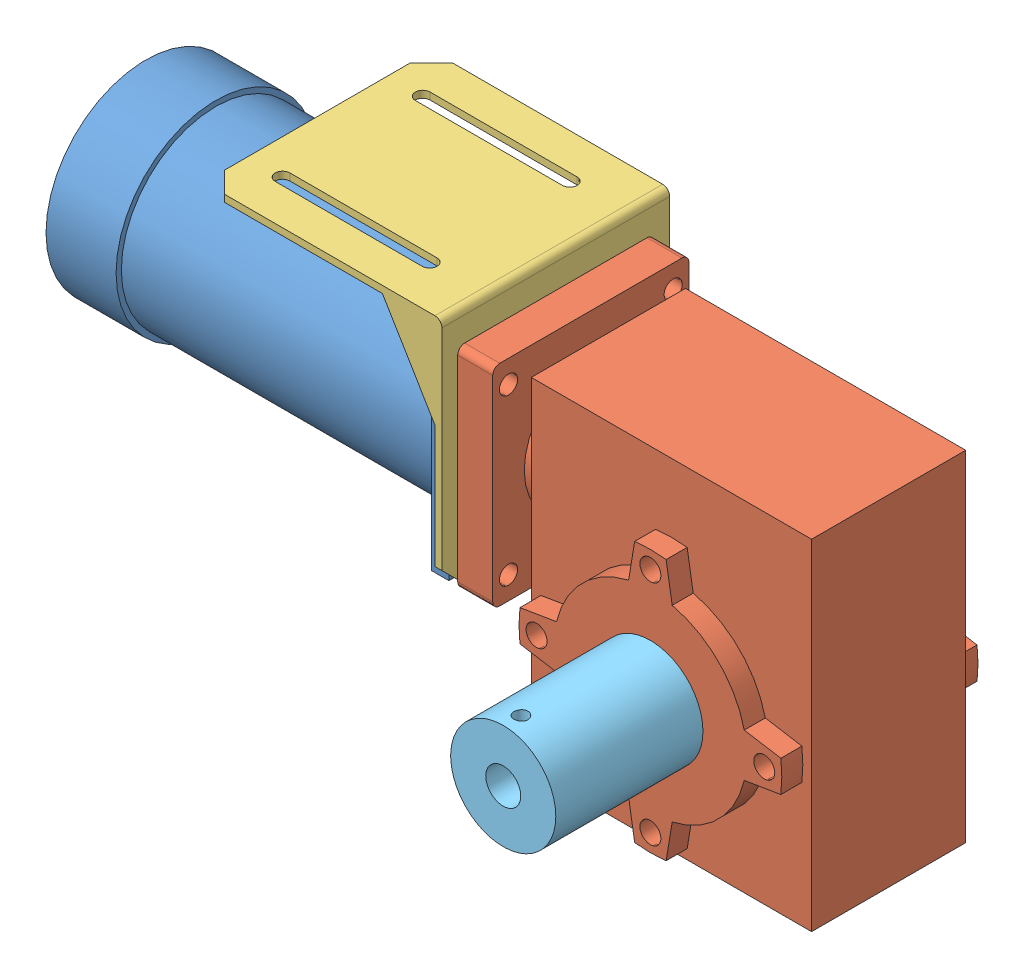
SolidWorks assembly 电机整套2, configuration 默认. Lengths in mm.
Overall size (212 109 102.5).
5 component instances, 5 part files, 10 mates.
Components (placement in the parent):
- 电机-1: 电机 [默认] at (7.9512 16.5957 136) size (136 57 57)
- 减速器-1: 减速器 [默认] at (54.7667 -0.0575 136) size (95 100 56)
- 电机安装支架-2: 电机安装支架 [默认] at (9.9512 55.5957 136) x (0 0 -1) z (-1 0 0) size (65 68 68)
- 14mm输出轴-1: 14mm输出轴 [默认] at (74.6611 -32.0715 154) x (0.994655 -0.103251 0) z (0 0 1) size (14 14 30)
- 联轴器-3: 联轴器 [默认] at (64.9512 -11.0307 206) x (-1 0 0) z (0 0 -1) size (30 30 42)
Mates (geometry in assembly coordinates):
- 同心2: concentric aligned: circle of 电机-1; cylinder of 减速器-1 through (9.9512 40.0957 159.5) axis (1 0 0) radius 2.6
- 同心4: concentric anti-aligned: cylinder of 电机-1 through (9.4512 16.5957 136) axis (-1 0 0) radius 19; cylinder of 电机安装支架-2 through (-58.0488 16.5957 136) axis (1 0 0) radius 19.1
- 重合4: coincident anti-aligned: plane of 电机-1 through (7.9512 16.5957 136) normal (1 0 0); plane of 电机安装支架-2 through (7.9512 -12.4043 103.5) normal (-1 0 0)
- 同心7: concentric anti-aligned: cylinder of 电机-1 through (28.9512 16.5957 136) axis (-1 0 0) radius 4; cylinder of 减速器-1 through (19.9512 16.5957 136) axis (1 0 0) radius 4
- 重合6: coincident anti-aligned: plane of 减速器-1 through (9.9512 44.5957 162) normal (-1 0 0); plane of 电机安装支架-2 through (9.9512 55.5957 103.5) normal (1 0 0)
- 同心8: concentric anti-aligned: cylinder of 减速器-1 through (64.9512 -13.4043 48) axis (0 0 1) radius 7; cylinder of 14mm输出轴-1 through (64.9512 -13.4043 203.949) axis (0 0 -1) radius 7
- 重合7: coincident anti-aligned: plane of 14mm输出轴-1 through (64.9512 -13.4043 184) normal (0 0 1); plane of 联轴器-3 through (64.9512 -13.4043 184) normal (0 0 -1)
- 同心9: concentric aligned: cylinder of 14mm输出轴-1 through (64.9512 -13.4043 184) axis (0 0 -1) radius 7; cylinder of 联轴器-3 through (64.9512 -13.4043 184) axis (0 0 -1) radius 7
- 同心10: concentric anti-aligned: cylinder of 减速器-1 through (64.9512 -13.4043 48) axis (0 0 1) radius 7; cylinder of 14mm输出轴-1 through (64.9512 -13.4043 184) axis (0 0 -1) radius 7
- 重合8: coincident anti-aligned: plane of 减速器-1 through (64.9512 -13.4043 164) normal (0 0 1); plane of 联轴器-3 through (64.9512 -13.4043 164) normal (0 0 -1)
